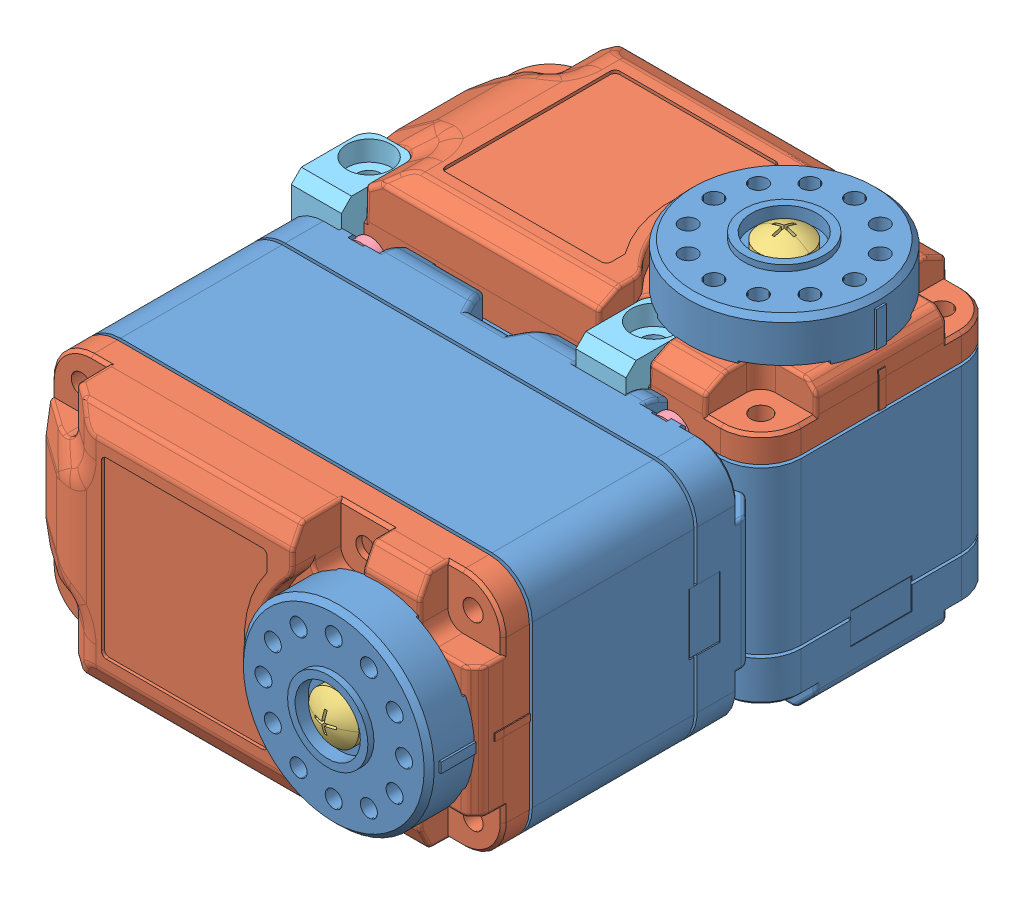
SolidWorks assembly herkulex_assembly, configuration Default. Lengths in mm.
Overall size (45.18 34.82 57.93).
24 component instances, 6 part files, 23 mates.
Components (placement in the parent):
- herkulex-1: herkulex [Default] at (12.5465 37.4768 20.4842) size (45.18 24.03 34.82)
  - Document-1: Document [Default] at origin size (45.03 24.02 34.35)
  - (#31287) TOP_191-1: (#31287) TOP_191 [Default] at (-8.4057 -18.0225 22.6771) x (1 0 0) z (0 1 0) size (45.18 8.06 24.03)
  - (#129725) KSB1023A_M2_5X8Z-1: (#129725) KSB1023A_M2_5X8Z [Default] at (17.6225 -18.0226 34.1771) x (0 0 -1) z (0 1 0) size (9.77 5 5)
  - (#112458) KSB1023A_T2X25NI-1: (#112458) KSB1023A_T2X25NI [Default] at (-10.3057 -28.0226 0.9771) x (0 0 1) z (0 1 0) size (26.48 3.4 3.4)
  - (#112458) KSB1023A_T2X25NI-2: (#112458) KSB1023A_T2X25NI [Default] at (19.8943 -28.0226 0.9771) x (0 0 1) z (0 1 0) size (26.48 3.4 3.4)
  - (#112458) KSB1023A_T2X25NI-3: (#112458) KSB1023A_T2X25NI [Default] at (19.8943 -8.0226 0.9771) x (0 0 1) z (0 1 0) size (26.48 3.4 3.4)
  - (#112458) KSB1023A_T2X25NI-4: (#112458) KSB1023A_T2X25NI [Default] at (-10.3057 -8.0226 0.9771) x (0 0 1) z (0 1 0) size (26.48 3.4 3.4)
- herkulex_L_bracket-1: herkulex_L_bracket [Default] at (28.669 12.9542 22.9613) x (0 0 -1) z (0 1 0) size (7.75 5 7.75)
- herkulex_L_bracket-2: herkulex_L_bracket [Default] at (23.669 25.9542 22.9613) x (0 0 -1) z (0 -1 0) size (7.75 5 7.75)
- herkulex_L_bracket-3: herkulex_L_bracket [Default] at (-4.6592 25.9542 22.9613) x (0 0 -1) z (0 -1 0) size (7.75 5 7.75)
- herkulex_L_bracket-4: herkulex_L_bracket [Default] at (0.3408 12.9542 22.9613) x (0 0 -1) z (0 1 0) size (7.75 5 7.75)
- herkulex-3: herkulex [Default] at (12.5465 5.2271 -9.3112) x (1 0 0) z (0 1 0) size (45.18 24.03 34.82)
  - Document-1: Document [Default] at origin size (45.03 24.02 34.35)
  - (#31287) TOP_191-1: (#31287) TOP_191 [Default] at (-8.4057 -18.0225 22.6771) x (1 0 0) z (0 1 0) size (45.18 8.06 24.03)
  - (#129725) KSB1023A_M2_5X8Z-1: (#129725) KSB1023A_M2_5X8Z [Default] at (17.6225 -18.0226 34.1771) x (0 0 -1) z (0 1 0) size (9.77 5 5)
  - (#112458) KSB1023A_T2X25NI-1: (#112458) KSB1023A_T2X25NI [Default] at (-10.3057 -28.0226 0.9771) x (0 0 1) z (0 1 0) size (26.48 3.4 3.4)
  - (#112458) KSB1023A_T2X25NI-2: (#112458) KSB1023A_T2X25NI [Default] at (19.8943 -28.0226 0.9771) x (0 0 1) z (0 1 0) size (26.48 3.4 3.4)
  - (#112458) KSB1023A_T2X25NI-3: (#112458) KSB1023A_T2X25NI [Default] at (19.8943 -8.0226 0.9771) x (0 0 1) z (0 1 0) size (26.48 3.4 3.4)
  - (#112458) KSB1023A_T2X25NI-4: (#112458) KSB1023A_T2X25NI [Default] at (-10.3057 -8.0226 0.9771) x (0 0 1) z (0 1 0) size (26.48 3.4 3.4)
- M2_hex_screw_91290A012-1: M2_hex_screw_91290A012 [91290A012] at (-2.1592 26.7042 17.7113) x (1 0 0) z (0 -1 0) size (3.8 3.8 7.09)
- M2_hex_screw_91290A012-2: M2_hex_screw_91290A012 [91290A012] at (26.169 26.7042 17.7113) x (1 0 0) z (0 -1 0) size (3.8 3.8 7.09)
- M2_hex_screw_91290A012-3: M2_hex_screw_91290A012 [91290A012] at (26.169 12.2042 17.7113) x (-0.837169 0 -0.546944) z (0 1 0) size (3.8 3.8 7.09)
- M2_hex_screw_91290A012-4: M2_hex_screw_91290A012 [91290A012] at (-2.1592 12.2042 17.7113) x (-0.837169 0 -0.546944) z (0 1 0) size (3.8 3.8 7.09)
Mates (geometry in assembly coordinates):
- Concentric1: concentric anti-aligned: cylinder of herkulex-1/Document-1 through (26.169 10.4542 23.2865) axis (0 0 1) radius 1; cylinder of herkulex_L_bracket-1 through (26.169 10.4542 20.4613) axis (0 0 -1) radius 1.2
- Coincident1: coincident anti-aligned: plane of herkulex-1/Document-1 through (23.669 7.7542 22.9613) normal (0 0 -1); plane of herkulex_L_bracket-1 through (23.669 12.9542 22.9613) normal (0 0 1)
- Parallel1: parallel anti-aligned: plane of herkulex-1/Document-1 through (35.8408 7.4542 27.0613) normal (0 -1 0); plane of herkulex_L_bracket-1 through (23.669 12.9542 20.4613) normal (0 1 0)
- Concentric2: concentric anti-aligned: cylinder of herkulex-1/Document-1 through (26.169 28.4542 23.2865) axis (0 0 1) radius 1; cylinder of herkulex_L_bracket-2 through (26.169 28.4542 20.4613) axis (0 0 -1) radius 1.2
- Coincident3: coincident anti-aligned: plane of herkulex-1/Document-1 through (23.669 25.9542 22.9613) normal (0 0 -1); plane of herkulex_L_bracket-2 through (28.669 25.9542 22.9613) normal (0 0 1)
- Parallel2: parallel anti-aligned: plane of herkulex-1/Document-1 through (-1.1592 31.4542 27.0613) normal (0 1 0); plane of herkulex_L_bracket-2 through (28.669 25.9542 20.4613) normal (0 -1 0)
- Concentric3: concentric anti-aligned: cylinder of herkulex-1/Document-1 through (-2.1592 28.4542 26.6613) axis (0 0 1) radius 1.1; cylinder of herkulex_L_bracket-3 through (-2.1592 28.4542 20.4613) axis (0 0 -1) radius 1.2
- Coincident4: coincident anti-aligned: plane of herkulex-1/Document-1 through (-4.9495 25.9542 22.9613) normal (0 0 -1); plane of herkulex_L_bracket-3 through (0.3408 25.9542 22.9613) normal (0 0 1)
- Parallel3: parallel anti-aligned: plane of herkulex-1/Document-1 through (-1.1592 31.4542 27.0613) normal (0 1 0); plane of herkulex_L_bracket-3 through (0.3408 25.9542 20.4613) normal (0 -1 0)
- Concentric4: concentric aligned: cylinder of herkulex-1/Document-1 through (-2.1592 10.4542 25.0113) axis (0 0 -1) radius 1; cylinder of herkulex_L_bracket-4 through (-2.1592 10.4542 20.4613) axis (0 0 -1) radius 1.2
- Coincident5: coincident anti-aligned: plane of herkulex-1/Document-1 through (-4.9495 7.702 22.9613) normal (0 0 -1); plane of herkulex_L_bracket-4 through (-4.6592 12.9542 22.9613) normal (0 0 1)
- Parallel4: parallel anti-aligned: plane of herkulex-1/Document-1 through (35.8408 7.4542 27.0613) normal (0 -1 0); plane of herkulex_L_bracket-4 through (-4.6592 12.9542 20.4613) normal (0 1 0)
- Concentric5: concentric aligned: cylinder of herkulex_L_bracket-4 through (-2.1592 5.2042 17.7113) axis (0 -1 0) radius 1.2; cylinder of herkulex-3/Document-1 through (-2.1592 9.7542 17.7113) axis (0 -1 0) radius 1
- Coincident6: coincident anti-aligned: plane of herkulex_L_bracket-4 through (-4.6592 7.7042 15.2113) normal (0 1 0); plane of herkulex-3/Document-1 through (-4.9495 7.7042 20.4636) normal (0 -1 0)
- Concentric6: concentric anti-aligned: cylinder of herkulex_L_bracket-1 through (26.169 5.2042 17.7113) axis (0 -1 0) radius 1.2; cylinder of herkulex-3/Document-1 through (26.169 8.0294 17.7113) axis (0 1 0) radius 1
- Concentric8: concentric anti-aligned: cylinder of herkulex_L_bracket-3 through (-2.1592 33.7042 17.7113) axis (0 1 0) radius 2.2; cylinder of M2_hex_screw_91290A012-1 through (-2.1592 33.7042 17.7113) axis (0 -1 0) radius 1.9
- Coincident8: coincident anti-aligned: plane of herkulex_L_bracket-3 through (-2.1592 31.7042 16.5113) normal (0 1 0); plane of M2_hex_screw_91290A012-1 through (-2.1592 31.7042 17.7113) normal (0 -1 0)
- Concentric9: concentric anti-aligned: cylinder of herkulex_L_bracket-2 through (26.169 33.7042 17.7113) axis (0 1 0) radius 2.2; cylinder of M2_hex_screw_91290A012-2 through (26.169 33.7042 17.7113) axis (0 -1 0) radius 1.9
- Coincident9: coincident anti-aligned: plane of herkulex_L_bracket-2 through (26.169 31.7042 16.5113) normal (0 1 0); plane of M2_hex_screw_91290A012-2 through (26.169 31.7042 17.7113) normal (0 -1 0)
- Concentric10: concentric anti-aligned: cylinder of herkulex_L_bracket-1 through (26.169 5.2042 17.7113) axis (0 -1 0) radius 2.2; cylinder of M2_hex_screw_91290A012-3 through (26.169 5.2042 17.7113) axis (0 1 0) radius 1.9
- Coincident10: coincident anti-aligned: plane of herkulex_L_bracket-1 through (26.169 7.2042 16.5113) normal (0 -1 0); plane of M2_hex_screw_91290A012-3 through (26.169 7.2042 17.7113) normal (0 1 0)
- Concentric11: concentric anti-aligned: cylinder of herkulex_L_bracket-4 through (-2.1592 5.2042 17.7113) axis (0 -1 0) radius 2.2; cylinder of M2_hex_screw_91290A012-4 through (-2.1592 5.2042 17.7113) axis (0 1 0) radius 1.9
- Coincident11: coincident anti-aligned: plane of herkulex_L_bracket-4 through (-2.1592 7.2042 16.5113) normal (0 -1 0); plane of M2_hex_screw_91290A012-4 through (-2.1592 7.2042 17.7113) normal (0 1 0)
